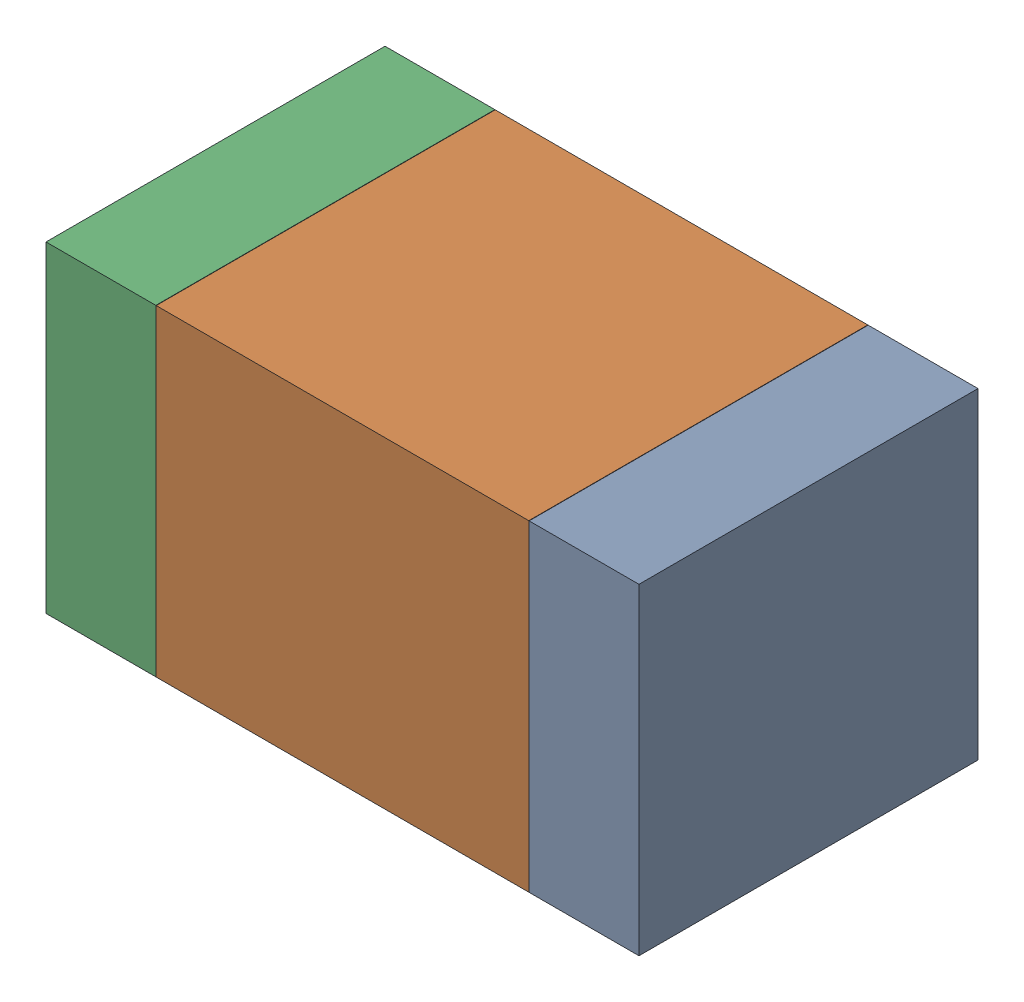
SolidWorks assembly C25, configuration Default. Lengths in mm.
Overall size (1.75 0.95 1).
6 component instances, 2 part files, 0 mates.
Components (placement in the parent):
- 6575498272-1: 6575498272 [Default] at (47.5755 5.207 0) size (0.32 0.95 1)
  - Extruded_8-1: Extruded_8 [Default] at origin size (0.32 0.95 1)
- 6575498112-1: 6575498112 [Default] at (46.863 5.207 0) size (1.1 0.95 1)
  - Extruded_9-1: Extruded_9 [Default] at origin size (1.1 0.95 1)
- 6575498272-2: 6575498272 [Default] at (46.1505 5.207 0) size (0.32 0.95 1)
  - Extruded_8-1: Extruded_8 [Default] at origin size (0.32 0.95 1)
